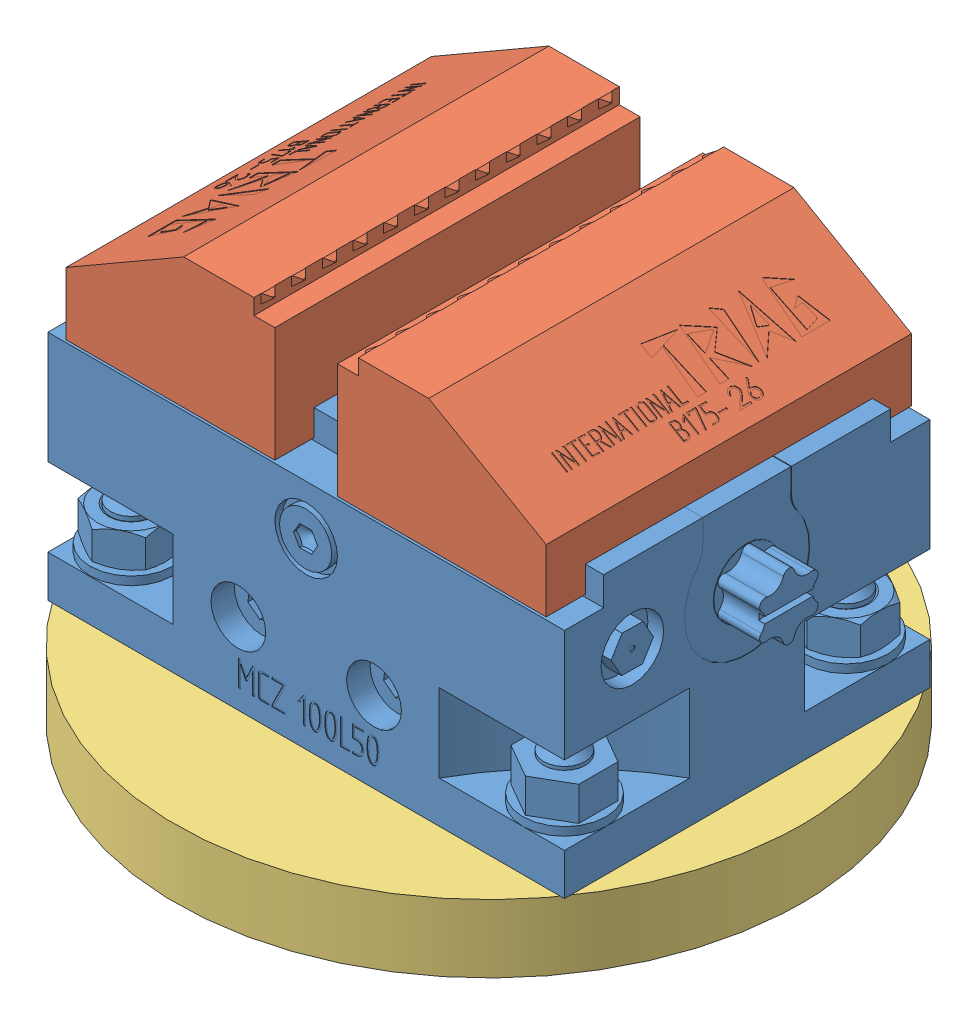
SolidWorks assembly ETAU 6-26mm, configuration Défaut. Lengths in mm.
Overall size (120 83 120).
4 component instances, 3 part files, 11 mates.
Components (placement in the parent):
- Copie de MCZ 100L50_KS^ETAU 6-26mm-1: Copie de MCZ 100L50_KS^ETAU 6-26mm [Défaut] at (0 0 30) size (107 62 70.1) (virtual)
- Copie de B175-26_KS^ETAU 6-26mm-1: Copie de B175-26_KS^ETAU 6-26mm [Défaut] at (38.25 43.436 0) x (0 0 -1) z (0 1 0) size (70 40 25) (virtual)
- Copie de B175-26_KS^ETAU 6-26mm-2: Copie de B175-26_KS^ETAU 6-26mm [Défaut] at (-38.25 43.436 0) x (0 0 1) z (0 1 0) size (70 40 25) (virtual)
- Copie de BASE ADAPT^ETAU 6-26mm-1: Copie de BASE ADAPT^ETAU 6-26mm [Défaut] at (0 -24.064 0) x (1 0 0) z (0 -1 0) size (120 120 13) (virtual)
Mates (geometry in assembly coordinates):
- Coïncidente1: coincident aligned: plane of Copie de MCZ 100L50_KS^ETAU 6-26mm-1 through (0 0 30) normal (1 0 0); plane of assembly through (0 0 0) normal (1 0 0)
- Coïncidente3: coincident aligned: plane of Copie de MCZ 100L50_KS^ETAU 6-26mm-1 through (0 0 0) normal (0 0 1); plane of assembly through (0 0 0) normal (0 0 1)
- Coïncidente4: coincident aligned: plane of Copie de MCZ 100L50_KS^ETAU 6-26mm-1 through (0 0 30) normal (0 1 0); plane of assembly through (0 0 0) normal (0 1 0)
- Coïncidente5: coincident anti-aligned: plane of Copie de B175-26_KS^ETAU 6-26mm-1 through (38.25 43.436 0) normal (0 0 -1); plane of assembly through (0 0 0) normal (0 0 1)
- Coïncidente6: coincident aligned: plane of Copie de B175-26_KS^ETAU 6-26mm-2 through (-38.25 43.436 0) normal (0 0 1); plane of assembly through (0 0 0) normal (0 0 1)
- Coïncidente7: coincident anti-aligned: plane of Copie de MCZ 100L50_KS^ETAU 6-26mm-1 through (49 25.936 0) normal (0 1 0); plane of Copie de B175-26_KS^ETAU 6-26mm-1 through (48 25.936 -30.25) normal (0 -1 0)
- Coïncidente9: coincident anti-aligned: plane of Copie de MCZ 100L50_KS^ETAU 6-26mm-1 through (49 25.936 0) normal (0 1 0); plane of Copie de B175-26_KS^ETAU 6-26mm-2 through (-48 25.936 30.25) normal (0 -1 0)
- Symétrique1: symmetric aligned: plane of Copie de MCZ 100L50_KS^ETAU 6-26mm-1 through (0 0 30) normal (1 0 0); plane of Copie de B175-26_KS^ETAU 6-26mm-2 through (-6 20.236 -38.5) normal (1 0 0); plane of Copie de B175-26_KS^ETAU 6-26mm-1 through (6 20.236 38.5) normal (-1 0 0)
- Distance1: distance = 20 mm anti-aligned: plane of Copie de B175-26_KS^ETAU 6-26mm-1 through (10 46.086 38.5) normal (-1 0 0); plane of Copie de B175-26_KS^ETAU 6-26mm-2 through (-10 46.086 -38.5) normal (1 0 0)
- Coïncidente10: coincident anti-aligned: plane of Copie de MCZ 100L50_KS^ETAU 6-26mm-1 through (10 -24.064 0) normal (0 -1 0); plane of Copie de BASE ADAPT^ETAU 6-26mm-1 through (0 -24.064 0) normal (0 1 0)
- Coaxiale1: concentric anti-aligned: cylinder of Copie de MCZ 100L50_KS^ETAU 6-26mm-1 through (0 -22.064 0) axis (0 -1 0) radius 11.7378; cylinder of Copie de BASE ADAPT^ETAU 6-26mm-1 through (0 -37.064 0) axis (0 1 0) radius 60
